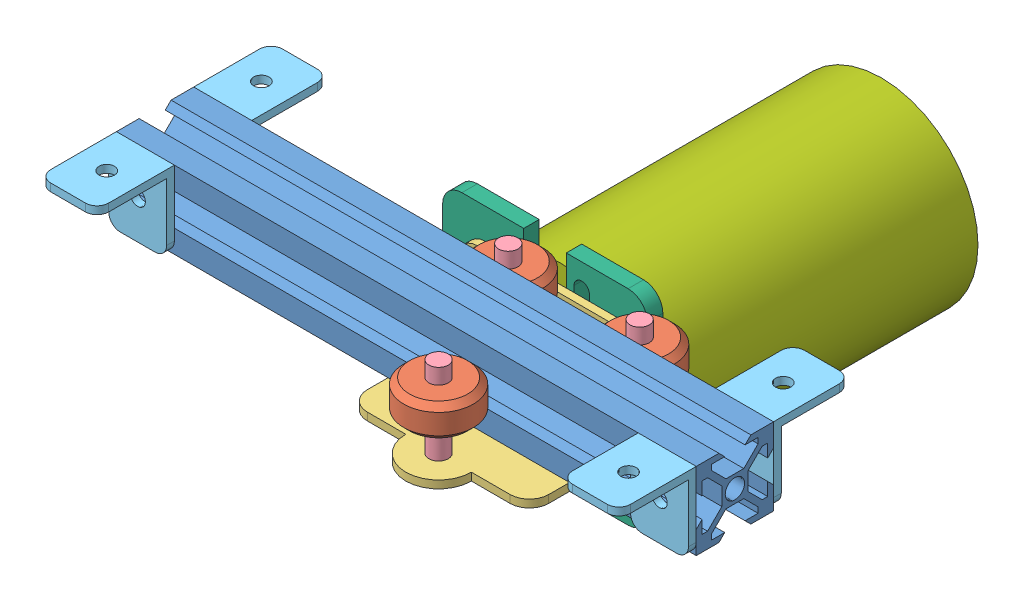
SolidWorks assembly Motor asembly, configuration Default. Lengths in mm.
Overall size (150 63.99 145.02).
17 component instances, 9 part files, 37 mates.
Components (placement in the parent):
- 2020_extrusion-1: 2020_extrusion [Default] at (126.062 16.2423 -20.3564) size (150 20 20)
- V-slot wheel-1: V-slot wheel [Default] at (215.5011 13.6123 -11.7399) x (0.98761 0 -0.15693) z (0 -1 0) size (18 18 8.26)
- V-slot wheel-2: V-slot wheel [Default] at (225.1504 13.6123 -39.8633) x (0.222988 0 -0.974821) z (0 -1 0) size (18 18 8.26)
- V-slot wheel-3: V-slot wheel [Default] at (206.2591 13.6123 -44.2588) x (0.710274 0 0.703925) z (0 -1 0) size (18 18 8.26)
- back plate-1: back plate [Default] at (216.921 1.3723 -28.698) x (-1 0 -0.000294) z (0.000294 0 -1) size (66.96 10 54.01)
- Part5^Motor asembly-1: Part5^Motor asembly [Default] at origin (virtual)
- fastener-1: fastener [Default] at (233.9237 1.3723 -37.8564) size (5 23 5)
- fastener-2: fastener [Default] at (216.9134 1.3723 -2.8514) size (5 23 5)
- fastener-3: fastener [Default] at (199.9237 1.3723 -37.8664) size (5 23 5)
- L_bracket-1: L_bracket [Default] at (261.062 26.2423 -8.3564) x (1 0 0) z (0 0 -1) size (15 20 20)
- L_bracket-2: L_bracket [Default] at (126.062 26.2423 -8.3564) x (1 0 0) z (0 0 -1) size (15 20 20)
- L_bracket-3: L_bracket [Default] at (141.062 26.2423 -32.3564) x (-1 0 0) z (0 0 1) size (15 20 20)
- L_bracket-4: L_bracket [Default] at (276.062 26.2423 -32.3564) x (-1 0 0) z (0 0 1) size (15 20 20)
- Motor Braket-1: Motor Braket [Default] at (172.4268 19.2423 -48.3745) x (1 0 0.000294) z (0.000294 0 -1) size (53 53 4)
- Motor-1: Motor [Default] at (198.9524 -12.7527 -135.3667) x (1 0 0.000294) z (-0.000294 0 1) size (50 50 103)
- small pulley-1: small pulley [Default] at (198.9265 -12.7527 -47.3667) x (1 0 0.000294) z (-0.000294 0 1) size (20 20 15)
- L_bracket-5: L_bracket [Default] at (225.4268 -0.6277 -48.3589) x (-1 0 -0.000294) z (0 1 0) size (15 20 20)
Mates (geometry in assembly coordinates):
- Distance1: distance = 5.135 mm anti-aligned: cylinder of V-slot wheel-2 through (233.9237 12.1123 -37.8564) axis (0 -1 0) radius 9; plane of 2020_extrusion-1 through (276.062 16.2423 -23.7214) normal (0 0 -1)
- Distance2: distance = 5.87 mm aligned: plane of V-slot wheel-2 through (226.6126 20.3723 -39.5288) normal (0 1 0); plane of 2020_extrusion-1 through (276.062 26.2423 -20.3564) normal (0 1 0)
- Distance3: distance = 5.87 mm aligned: plane of 2020_extrusion-1 through (276.062 26.2423 -20.3564) normal (0 1 0); plane of V-slot wheel-1 through (215.7365 20.3723 -10.2584) normal (0 1 0)
- Distance5: distance = 5.14 mm anti-aligned: cylinder of V-slot wheel-1 through (216.9134 12.1123 -2.8514) axis (0 -1 0) radius 9; plane of 2020_extrusion-1 through (276.062 16.2423 -16.9914) normal (0 0 1)
- Distance6: distance = 5.87 mm aligned: plane of V-slot wheel-3 through (205.2032 20.3723 -43.1934) normal (0 1 0); plane of 2020_extrusion-1 through (276.062 26.2423 -20.3564) normal (0 1 0)
- Concentric1: concentric anti-aligned: cylinder of V-slot wheel-2 through (233.9237 12.1123 -37.8564) axis (0 1 0) radius 2.5; cylinder of back plate-1 through (233.9237 3.3723 -37.8564) axis (0 -1 0) radius 2.5
- Concentric2: concentric anti-aligned: cylinder of V-slot wheel-1 through (216.9134 12.1123 -2.8514) axis (0 1 0) radius 2.5; cylinder of back plate-1 through (216.9134 3.3723 -2.8514) axis (0 -1 0) radius 2.5
- Concentric7: concentric anti-aligned: cylinder of V-slot wheel-3 through (199.9237 12.1123 -37.8664) axis (0 1 0) radius 2.5; cylinder of back plate-1 through (199.9237 3.3723 -37.8664) axis (0 -1 0) radius 2.5
- Coincident5: coincident anti-aligned: circle of back plate-1; cylinder of fastener-3 through (199.9237 24.3723 -37.8664) axis (0 -1 0) radius 2.5
- Concentric8: concentric aligned: cylinder of back plate-1 through (233.9237 3.3723 -37.8564) axis (0 -1 0) radius 2.5; cylinder of fastener-1 through (233.9237 24.3723 -37.8564) axis (0 -1 0) radius 2.5
- Concentric9: concentric aligned: cylinder of back plate-1 through (216.9134 3.3723 -2.8514) axis (0 -1 0) radius 2.5; cylinder of fastener-2 through (216.9134 24.3723 -2.8514) axis (0 -1 0) radius 2.5
- Coincident7: coincident aligned: plane of back plate-1 through (235.4254 1.3723 -43.3559) normal (0 -1 0); plane of fastener-1 through (233.9237 1.3723 -37.8564) normal (0 -1 0)
- Coincident8: coincident aligned: plane of back plate-1 through (235.4254 1.3723 -43.3559) normal (0 -1 0); plane of fastener-2 through (216.9134 1.3723 -2.8514) normal (0 -1 0)
- Coincident9: coincident aligned: plane of back plate-1 through (235.4254 1.3723 -43.3559) normal (0 -1 0); plane of fastener-3 through (199.9237 1.3723 -37.8664) normal (0 -1 0)
- Distance8: distance = 4 mm aligned: plane of fastener-2 through (216.9134 24.3723 -2.8514) normal (0 1 0); plane of V-slot wheel-1 through (215.7365 20.3723 -10.2584) normal (0 1 0)
- Coincident11: coincident anti-aligned: plane of 2020_extrusion-1 through (276.062 16.2423 -10.3564) normal (0 0 1); plane of L_bracket-1 through (261.062 26.2423 -10.3564) normal (0 0 -1)
- Coincident12: coincident aligned: line of 2020_extrusion-1 through (276.062 6.2423 -10.3564) axis (-1 0 0); line of L_bracket-1 through (273.062 6.2423 -10.3564) axis (-1 0 0)
- Coincident13: coincident aligned: plane of 2020_extrusion-1 through (276.062 16.2423 -20.3564) normal (1 0 0); plane of L_bracket-1 through (276.062 24.2423 6.6436) normal (1 0 0)
- Coincident14: coincident anti-aligned: plane of 2020_extrusion-1 through (276.062 16.2423 -10.3564) normal (0 0 1); plane of L_bracket-2 through (126.062 26.2423 -10.3564) normal (0 0 -1)
- Coincident15: coincident aligned: plane of 2020_extrusion-1 through (126.062 16.2423 -20.3564) normal (-1 0 0); plane of L_bracket-2 through (126.062 24.2423 -8.3564) normal (-1 0 0)
- Coincident16: coincident aligned: plane of 2020_extrusion-1 through (276.062 6.2423 -20.3564) normal (0 -1 0); plane of L_bracket-2 through (126.062 6.2423 -10.3564) normal (0 -1 0)
- Coincident17: coincident anti-aligned: plane of 2020_extrusion-1 through (276.062 16.2423 -30.3564) normal (0 0 -1); plane of L_bracket-3 through (141.062 26.2423 -30.3564) normal (0 0 1)
- Coincident18: coincident aligned: plane of 2020_extrusion-1 through (126.062 16.2423 -20.3564) normal (-1 0 0); plane of L_bracket-3 through (126.062 24.2423 -47.3564) normal (-1 0 0)
- Coincident19: coincident aligned: plane of 2020_extrusion-1 through (276.062 6.2423 -20.3564) normal (0 -1 0); plane of L_bracket-3 through (141.062 6.2423 -30.3564) normal (0 -1 0)
- Coincident20: coincident aligned: plane of 2020_extrusion-1 through (276.062 16.2423 -20.3564) normal (1 0 0); plane of L_bracket-4 through (276.062 24.2423 -32.3564) normal (1 0 0)
- Coincident21: coincident anti-aligned: plane of 2020_extrusion-1 through (276.062 16.2423 -30.3564) normal (0 0 -1); plane of L_bracket-4 through (276.062 26.2423 -30.3564) normal (0 0 1)
- Coincident22: coincident aligned: plane of 2020_extrusion-1 through (276.062 6.2423 -20.3564) normal (0 -1 0); plane of L_bracket-4 through (276.062 6.2423 -30.3564) normal (0 -1 0)
- Coincident23: coincident anti-aligned: plane of back plate-1 through (235.4268 3.3723 -48.3559) normal (0.000294 0 -1); plane of Motor Braket-1 through (172.4268 19.2423 -48.3745) normal (-0.000294 0 1)
- Distance10: distance = 5 mm anti-aligned: plane of L_bracket-3 through (138.062 24.2423 -47.3564) normal (0 -1 0); plane of Motor Braket-1 through (172.428 19.2423 -52.3745) normal (0 1 0)
- Distance9: distance = 10 mm aligned: plane of Motor Braket-1 through (225.428 19.2423 -52.3589) normal (1 0 0.000294); plane of back plate-1 through (235.4262 11.3723 -46.3559) normal (1 0 0.000294)
- Concentric10: concentric anti-aligned: cylinder of Motor Braket-1 through (198.928 -12.7527 -52.3667) axis (-0.000294 0 1) radius 5.5; cylinder of Motor-1 through (198.9221 -12.7527 -32.3667) axis (0.000294 0 -1) radius 3
- Coincident26: coincident anti-aligned: plane of Motor Braket-1 through (172.428 19.2423 -52.3745) normal (0.000294 0 -1); plane of Motor-1 through (198.928 -12.7527 -52.3667) normal (-0.000294 0 1)
- Concentric11: concentric aligned: cylinder of Motor-1 through (198.9221 -12.7527 -32.3667) axis (0.000294 0 -1) radius 3; cylinder of small pulley-1 through (198.9221 -12.7527 -32.3667) axis (0.000294 0 -1) radius 3
- Coincident27: coincident aligned: plane of Motor-1 through (198.9221 -12.7527 -32.3667) normal (-0.000294 0 1); plane of small pulley-1 through (198.9221 -12.7527 -32.3667) normal (-0.000294 0 1)
- Coincident28: coincident anti-aligned: plane of Motor Braket-1 through (172.4268 19.2423 -48.3745) normal (-0.000294 0 1); plane of L_bracket-5 through (222.4268 -15.6277 -48.3598) normal (0.000294 0 -1)
- Coincident29: coincident aligned: plane of Motor Braket-1 through (225.428 19.2423 -52.3589) normal (1 0 0.000294); plane of L_bracket-5 through (225.4262 -0.6277 -46.3589) normal (1 0 0.000294)
- Coincident30: coincident anti-aligned: plane of back plate-1 through (235.4254 1.3723 -43.3559) normal (0 -1 0); plane of L_bracket-5 through (225.4268 1.3723 -48.3589) normal (0 1 0)
